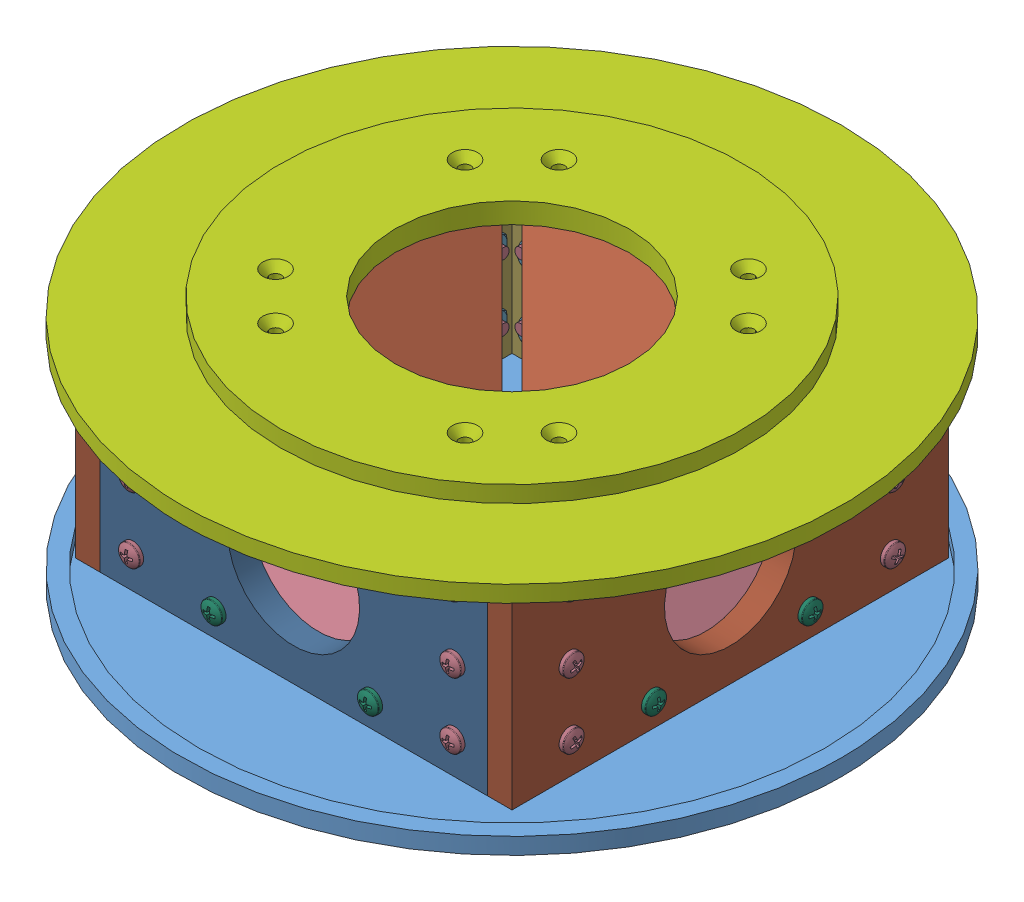
SolidWorks assembly Spinner assembly, configuration Default. Lengths in mm.
Overall size (254 134.94 254).
133 component instances, 16 part files, 69 mates.
Components (placement in the parent):
- bottom spinner plate-1: bottom spinner plate [Default] x (0 0 -1) z (1 0 0) size (254 6.35 254)
- Magnet Assembly-1: Magnet Assembly [Default] at (7.3988 45.9633 51.8347) size (82.55 82.55 29.53)
  - magnet holder-1: magnet holder [Default] at (-7.3988 1.6617 -6.7497) size (82.55 82.55 18.1)
  - Magnet 31-1: Magnet 31 [Default] at (-7.3988 1.6617 -5.1622) x (0.999112 -0.042142 0) z (0 0 1) size (76.2 76.2 25.4)
  - magnet plate-1: magnet plate [Default] at (-7.3988 1.6617 11.3478) size (82.55 82.55 11.43)
  - CR-FHMS 0.164-32x1x1-N-1: CR-FHMS 0.164-32x1x1-N [CR-FHMS 0.164-32x1x1-N] at (-32.7988 36.5867 21.9997) x (0 0 -1) z (-0.169258 0.985572 0) size (25.4 7.42 7.42)
  - CR-FHMS 0.164-32x1x1-N-5: CR-FHMS 0.164-32x1x1-N [CR-FHMS 0.164-32x1x1-N] at (-32.7988 -33.2633 21.9997) x (0 0 -1) z (0.981591 0.190995 0) size (25.4 7.42 7.42)
  - CR-FHMS 0.164-32x1x1-N-6: CR-FHMS 0.164-32x1x1-N [CR-FHMS 0.164-32x1x1-N] at (18.0012 -33.2633 21.9997) x (0 0 -1) z (1 0 0) size (25.4 7.42 7.42)
  - CR-FHMS 0.164-32x1x1-N-7: CR-FHMS 0.164-32x1x1-N [CR-FHMS 0.164-32x1x1-N] at (18.0012 36.5867 21.9997) x (0 0 -1) z (1 0 0) size (25.4 7.42 7.42)
- HX-SHCS 0.19-24x1x1-N-1: HX-SHCS 0.19-24x1x1-N [HX-SHCS 0.19-24x1x1-N] at (-54.61 -4.826 -36.5125) x (0 1 0) z (0 0 1) size (30.23 7.94 7.94)
- top spinner plate-1: top spinner plate [Default] at (0 84.1375 0) size (254 12.7 254)
- Spinner Hub-1: Spinner Hub [Default] x (-0.92388 0 -0.382683) z (-0.382683 0 0.92388) size (76.2 38.1 76.2)
- CR-FHM1 0.164-32x0.875x0.875-N-25: CR-FHM1 0.164-32x0.875x0.875-N [CR-FHM1 0.164-32x0.875x0.875-N] at (0 6.3377 31.75) x (0 -1 0) z (0 0 1) size (22.23 7.24 7.24)
- CR-FHM1 0.164-32x0.875x0.875-N-26: CR-FHM1 0.164-32x0.875x0.875-N [CR-FHM1 0.164-32x0.875x0.875-N] at (22.4506 6.3377 22.4506) x (0 -1 0) z (0.707107 0 0.707107) size (22.23 7.24 7.24)
- CR-FHM1 0.164-32x0.875x0.875-N-27: CR-FHM1 0.164-32x0.875x0.875-N [CR-FHM1 0.164-32x0.875x0.875-N] at (31.75 6.3377 0) x (0 -1 0) z (1 0 0) size (22.23 7.24 7.24)
- CR-FHM1 0.164-32x0.875x0.875-N-28: CR-FHM1 0.164-32x0.875x0.875-N [CR-FHM1 0.164-32x0.875x0.875-N] at (22.4506 6.3377 -22.4506) x (0 -1 0) z (0.707107 0 -0.707107) size (22.23 7.24 7.24)
- CR-FHM1 0.164-32x0.875x0.875-N-29: CR-FHM1 0.164-32x0.875x0.875-N [CR-FHM1 0.164-32x0.875x0.875-N] at (0 6.3377 -31.75) x (0 -1 0) z (0 0 -1) size (22.23 7.24 7.24)
- CR-FHM1 0.164-32x0.875x0.875-N-30: CR-FHM1 0.164-32x0.875x0.875-N [CR-FHM1 0.164-32x0.875x0.875-N] at (-22.4506 6.3377 -22.4506) x (0 -1 0) z (-0.707107 0 -0.707107) size (22.23 7.24 7.24)
- CR-FHM1 0.164-32x0.875x0.875-N-31: CR-FHM1 0.164-32x0.875x0.875-N [CR-FHM1 0.164-32x0.875x0.875-N] at (-31.75 6.3377 0) x (0 -1 0) z (-1 0 0) size (22.23 7.24 7.24)
- CR-FHM1 0.164-32x0.875x0.875-N-32: CR-FHM1 0.164-32x0.875x0.875-N [CR-FHM1 0.164-32x0.875x0.875-N] at (-22.4506 6.3377 22.4506) x (0 -1 0) z (-0.707107 0 0.707107) size (22.23 7.24 7.24)
- Magnet Assembly-5: Magnet Assembly [Default] at (7.3988 49.2867 -51.8347) x (1 0 0) z (0 0 -1) size (82.55 82.55 29.53)
  - magnet holder-1: magnet holder [Default] at (-7.3988 1.6617 -6.7497) size (82.55 82.55 18.1)
  - Magnet 31-1: Magnet 31 [Default] at (-7.3988 1.6617 -5.1622) x (0.999112 -0.042142 0) z (0 0 1) size (76.2 76.2 25.4)
  - magnet plate-1: magnet plate [Default] at (-7.3988 1.6617 11.3478) size (82.55 82.55 11.43)
  - CR-FHMS 0.164-32x1x1-N-1: CR-FHMS 0.164-32x1x1-N [CR-FHMS 0.164-32x1x1-N] at (-32.7988 36.5867 21.9997) x (0 0 -1) z (-0.169258 0.985572 0) size (25.4 7.42 7.42)
  - CR-FHMS 0.164-32x1x1-N-5: CR-FHMS 0.164-32x1x1-N [CR-FHMS 0.164-32x1x1-N] at (-32.7988 -33.2633 21.9997) x (0 0 -1) z (0.981591 0.190995 0) size (25.4 7.42 7.42)
  - CR-FHMS 0.164-32x1x1-N-6: CR-FHMS 0.164-32x1x1-N [CR-FHMS 0.164-32x1x1-N] at (18.0012 -33.2633 21.9997) x (0 0 -1) z (1 0 0) size (25.4 7.42 7.42)
  - CR-FHMS 0.164-32x1x1-N-7: CR-FHMS 0.164-32x1x1-N [CR-FHMS 0.164-32x1x1-N] at (18.0012 36.5867 21.9997) x (0 0 -1) z (1 0 0) size (25.4 7.42 7.42)
- End Shunt-1: End Shunt [Default] at (-74.6125 47.625 -79.375) x (0 0 -1) z (1 0 0) size (9.53 76.2 149.22)
- End Shunt-2: End Shunt [Default] at (74.6125 47.625 79.375) x (0 0 1) z (-1 0 0) size (9.53 76.2 149.22)
- Side Shunt-1: Side Shunt [Default] at (79.375 47.625 -84.1375) size (9.53 76.2 168.28)
- Side Shunt-2: Side Shunt [Default] at (-79.375 47.625 -84.1375) size (9.53 76.2 168.28)
- Shunt Gusset-1: Shunt Gusset [Default] at (74.6125 85.725 74.6125) x (-1 0 0) z (0 -1 0) size (25.4 25.4 79.38)
- CR-PHMS 0.164-32x0.75x0.75-N-1: CR-PHMS 0.164-32x0.75x0.75-N [CR-PHMS 0.164-32x0.75x0.75-N] at (87.0585 73.025 61.9125) x (-1 0 0) z (0 0.924225 0.381849) size (21.93 8.18 8.18)
- CR-PHMS 0.164-32x0.75x0.75-N-2: CR-PHMS 0.164-32x0.75x0.75-N [CR-PHMS 0.164-32x0.75x0.75-N] at (87.0585 47.625 61.9125) x (-1 0 0) z (0 0.924225 0.381849) size (21.93 8.18 8.18)
- CR-PHMS 0.164-32x0.75x0.75-N-3: CR-PHMS 0.164-32x0.75x0.75-N [CR-PHMS 0.164-32x0.75x0.75-N] at (87.0585 22.225 61.9125) x (-1 0 0) z (0 0.924225 0.381849) size (21.93 8.18 8.18)
- CR-PHMS 0.164-32x0.75x0.75-N-4: CR-PHMS 0.164-32x0.75x0.75-N [CR-PHMS 0.164-32x0.75x0.75-N] at (61.9125 22.225 87.0585) x (0 0 -1) z (1 0 0) size (21.93 8.18 8.18)
- CR-PHMS 0.164-32x0.75x0.75-N-5: CR-PHMS 0.164-32x0.75x0.75-N [CR-PHMS 0.164-32x0.75x0.75-N] at (61.9125 47.625 87.0585) x (0 0 -1) z (1 0 0) size (21.93 8.18 8.18)
- CR-PHMS 0.164-32x0.75x0.75-N-6: CR-PHMS 0.164-32x0.75x0.75-N [CR-PHMS 0.164-32x0.75x0.75-N] at (61.9125 73.025 87.0585) x (0 0 -1) z (1 0 0) size (21.93 8.18 8.18)
- MSHXNUT 0.164-32-S-N-66: MSHXNUT 0.164-32-S-N [MSHXNUT 0.164-32-S-N] at (68.1355 73.025 61.9125) x (0 0 1) z (-1 0 0) size (8.74 10.09 3.3)
- MSHXNUT 0.164-32-S-N-67: MSHXNUT 0.164-32-S-N [MSHXNUT 0.164-32-S-N] at (68.1355 47.625 61.9125) x (0 0 1) z (-1 0 0) size (8.74 10.09 3.3)
- MSHXNUT 0.164-32-S-N-68: MSHXNUT 0.164-32-S-N [MSHXNUT 0.164-32-S-N] at (61.9125 69.85 68.1355) x (0.923728 0.383049 0) z (0 0 -1) size (8.74 10.09 3.3)
- MSHXNUT 0.164-32-S-N-69: MSHXNUT 0.164-32-S-N [MSHXNUT 0.164-32-S-N] at (61.9125 44.45 68.1355) x (0.923728 0.383049 0) z (0 0 -1) size (8.74 10.09 3.3)
- MSHXNUT 0.164-32-S-N-70: MSHXNUT 0.164-32-S-N [MSHXNUT 0.164-32-S-N] at (61.9125 19.05 68.1355) x (0.923728 0.383049 0) z (0 0 -1) size (8.74 10.09 3.3)
- MSHXNUT 0.164-32-S-N-71: MSHXNUT 0.164-32-S-N [MSHXNUT 0.164-32-S-N] at (68.1355 22.225 61.9125) x (0 0 1) z (-1 0 0) size (8.74 10.09 3.3)
- CR-PHMS 0.164-32x1.25x1-N-7: CR-PHMS 0.164-32x1.25x1-N [CR-PHMS 0.164-32x1.25x1-N] at (30.1625 76.2 87.0585) x (0 0 -1) z (1 0 0) size (34.63 8.18 8.18)
- CR-PHMS 0.164-32x1.25x1-N-8: CR-PHMS 0.164-32x1.25x1-N [CR-PHMS 0.164-32x1.25x1-N] at (30.1625 19.05 87.0585) x (0 0 -1) z (1 0 0) size (34.63 8.18 8.18)
- CR-PHMS 0.164-32x1.25x1-N-9: CR-PHMS 0.164-32x1.25x1-N [CR-PHMS 0.164-32x1.25x1-N] at (-30.1625 19.05 87.0585) x (0 0 -1) z (1 0 0) size (34.63 8.18 8.18)
- CR-PHMS 0.164-32x1.25x1-N-10: CR-PHMS 0.164-32x1.25x1-N [CR-PHMS 0.164-32x1.25x1-N] at (-30.1625 76.2 87.0585) x (0 0 -1) z (1 0 0) size (34.63 8.18 8.18)
- MSHXNUT 0.164-32-S-N-72: MSHXNUT 0.164-32-S-N [MSHXNUT 0.164-32-S-N] at (0 -12.827 31.75) x (1 0 0) z (0 -1 0) size (8.74 10.09 3.3)
- MSHXNUT 0.164-32-S-N-80: MSHXNUT 0.164-32-S-N [MSHXNUT 0.164-32-S-N] at (22.4506 -12.827 22.4506) x (0.707107 0 -0.707107) z (0 -1 0) size (8.74 10.09 3.3)
- MSHXNUT 0.164-32-S-N-81: MSHXNUT 0.164-32-S-N [MSHXNUT 0.164-32-S-N] at (31.75 -12.827 0) x (0 0 -1) z (0 -1 0) size (8.74 10.09 3.3)
- MSHXNUT 0.164-32-S-N-82: MSHXNUT 0.164-32-S-N [MSHXNUT 0.164-32-S-N] at (22.4506 -12.827 -22.4506) x (-0.707107 0 -0.707107) z (0 -1 0) size (8.74 10.09 3.3)
- MSHXNUT 0.164-32-S-N-83: MSHXNUT 0.164-32-S-N [MSHXNUT 0.164-32-S-N] at (0 -12.827 -31.75) x (-1 0 0) z (0 -1 0) size (8.74 10.09 3.3)
- MSHXNUT 0.164-32-S-N-84: MSHXNUT 0.164-32-S-N [MSHXNUT 0.164-32-S-N] at (-22.4506 -12.827 -22.4506) x (-0.707107 0 0.707107) z (0 -1 0) size (8.74 10.09 3.3)
- MSHXNUT 0.164-32-S-N-85: MSHXNUT 0.164-32-S-N [MSHXNUT 0.164-32-S-N] at (-31.75 -12.827 0) x (0 0 1) z (0 -1 0) size (8.74 10.09 3.3)
- MSHXNUT 0.164-32-S-N-86: MSHXNUT 0.164-32-S-N [MSHXNUT 0.164-32-S-N] at (-22.4506 -12.827 22.4506) x (0.707107 0 0.707107) z (0 -1 0) size (8.74 10.09 3.3)
- CR-PHMS 0.164-32x1.25x1-N-29: CR-PHMS 0.164-32x1.25x1-N [CR-PHMS 0.164-32x1.25x1-N] at (-30.1625 76.2 -87.0585) x (0 0 1) z (-1 0 0) size (34.63 8.18 8.18)
- CR-PHMS 0.164-32x1.25x1-N-30: CR-PHMS 0.164-32x1.25x1-N [CR-PHMS 0.164-32x1.25x1-N] at (-30.1625 19.05 -87.0585) x (0 0 1) z (-1 0 0) size (34.63 8.18 8.18)
- CR-PHMS 0.164-32x1.25x1-N-31: CR-PHMS 0.164-32x1.25x1-N [CR-PHMS 0.164-32x1.25x1-N] at (30.1625 76.2 -87.0585) x (0 0 1) z (-1 0 0) size (34.63 8.18 8.18)
- CR-PHMS 0.164-32x1.25x1-N-32: CR-PHMS 0.164-32x1.25x1-N [CR-PHMS 0.164-32x1.25x1-N] at (30.1625 19.05 -87.0585) x (0 0 1) z (-1 0 0) size (34.63 8.18 8.18)
- CR-PHMS 0.164-32x0.75x0.75-N-33: CR-PHMS 0.164-32x0.75x0.75-N [CR-PHMS 0.164-32x0.75x0.75-N] at (-87.0585 73.025 61.9125) x (1 0 0) z (0 -0.924225 -0.381849) size (21.93 8.18 8.18)
- CR-PHMS 0.164-32x0.75x0.75-N-34: CR-PHMS 0.164-32x0.75x0.75-N [CR-PHMS 0.164-32x0.75x0.75-N] at (-87.0585 47.625 61.9125) x (1 0 0) z (0 -0.924225 -0.381849) size (21.93 8.18 8.18)
- CR-PHMS 0.164-32x0.75x0.75-N-35: CR-PHMS 0.164-32x0.75x0.75-N [CR-PHMS 0.164-32x0.75x0.75-N] at (-87.0585 22.225 61.9125) x (1 0 0) z (0 -0.924225 -0.381849) size (21.93 8.18 8.18)
- CR-PHMS 0.164-32x0.75x0.75-N-36: CR-PHMS 0.164-32x0.75x0.75-N [CR-PHMS 0.164-32x0.75x0.75-N] at (-61.9125 73.025 87.0585) x (0 0 -1) z (1 0 0) size (21.93 8.18 8.18)
- CR-PHMS 0.164-32x0.75x0.75-N-37: CR-PHMS 0.164-32x0.75x0.75-N [CR-PHMS 0.164-32x0.75x0.75-N] at (-61.9125 47.625 87.0585) x (0 0 -1) z (1 0 0) size (21.93 8.18 8.18)
- CR-PHMS 0.164-32x0.75x0.75-N-38: CR-PHMS 0.164-32x0.75x0.75-N [CR-PHMS 0.164-32x0.75x0.75-N] at (-61.9125 22.225 87.0585) x (0 0 -1) z (1 0 0) size (21.93 8.18 8.18)
- Shunt Gusset-2: Shunt Gusset [Default] at (-74.6125 6.35 74.6125) x (1 0 0) z (0 1 0) size (25.4 25.4 79.38)
- MSHXNUT 0.164-32-S-N-90: MSHXNUT 0.164-32-S-N [MSHXNUT 0.164-32-S-N] at (-61.9125 69.85 68.1355) x (0.923728 -0.383049 0) z (0 0 -1) size (8.74 10.09 3.3)
- MSHXNUT 0.164-32-S-N-91: MSHXNUT 0.164-32-S-N [MSHXNUT 0.164-32-S-N] at (-61.9125 44.45 68.1355) x (0.923728 -0.383049 0) z (0 0 -1) size (8.74 10.09 3.3)
- MSHXNUT 0.164-32-S-N-92: MSHXNUT 0.164-32-S-N [MSHXNUT 0.164-32-S-N] at (-61.9125 19.05 68.1355) x (0.923728 -0.383049 0) z (0 0 -1) size (8.74 10.09 3.3)
- MSHXNUT 0.164-32-S-N-93: MSHXNUT 0.164-32-S-N [MSHXNUT 0.164-32-S-N] at (-68.1355 22.225 61.9125) x (0 0 -1) z (1 0 0) size (8.74 10.09 3.3)
- MSHXNUT 0.164-32-S-N-94: MSHXNUT 0.164-32-S-N [MSHXNUT 0.164-32-S-N] at (-68.1355 47.625 61.9125) x (0 0 -1) z (1 0 0) size (8.74 10.09 3.3)
- MSHXNUT 0.164-32-S-N-87: MSHXNUT 0.164-32-S-N [MSHXNUT 0.164-32-S-N] at (-68.1355 73.025 61.9125) x (0 0 -1) z (1 0 0) size (8.74 10.09 3.3)
- CR-PHMS 0.164-32x0.75x0.75-N-39: CR-PHMS 0.164-32x0.75x0.75-N [CR-PHMS 0.164-32x0.75x0.75-N] at (87.0585 73.025 -61.9125) x (-1 0 0) z (0 -0.924225 0.381849) size (21.93 8.18 8.18)
- CR-PHMS 0.164-32x0.75x0.75-N-40: CR-PHMS 0.164-32x0.75x0.75-N [CR-PHMS 0.164-32x0.75x0.75-N] at (87.0585 47.625 -61.9125) x (-1 0 0) z (0 -0.924225 0.381849) size (21.93 8.18 8.18)
- CR-PHMS 0.164-32x0.75x0.75-N-41: CR-PHMS 0.164-32x0.75x0.75-N [CR-PHMS 0.164-32x0.75x0.75-N] at (87.0585 22.225 -61.9125) x (-1 0 0) z (0 -0.924225 0.381849) size (21.93 8.18 8.18)
- CR-PHMS 0.164-32x0.75x0.75-N-42: CR-PHMS 0.164-32x0.75x0.75-N [CR-PHMS 0.164-32x0.75x0.75-N] at (61.9125 73.025 -87.0585) x (0 0 1) z (-1 0 0) size (21.93 8.18 8.18)
- CR-PHMS 0.164-32x0.75x0.75-N-43: CR-PHMS 0.164-32x0.75x0.75-N [CR-PHMS 0.164-32x0.75x0.75-N] at (61.9125 47.625 -87.0585) x (0 0 1) z (-1 0 0) size (21.93 8.18 8.18)
- CR-PHMS 0.164-32x0.75x0.75-N-44: CR-PHMS 0.164-32x0.75x0.75-N [CR-PHMS 0.164-32x0.75x0.75-N] at (61.9125 22.225 -87.0585) x (0 0 1) z (-1 0 0) size (21.93 8.18 8.18)
- Shunt Gusset-3: Shunt Gusset [Default] at (74.6125 6.35 -74.6125) x (-1 0 0) z (0 1 0) size (25.4 25.4 79.38)
- MSHXNUT 0.164-32-S-N-95: MSHXNUT 0.164-32-S-N [MSHXNUT 0.164-32-S-N] at (61.9125 69.85 -68.1355) x (-0.923728 -0.383049 0) z (0 0 1) size (8.74 10.09 3.3)
- MSHXNUT 0.164-32-S-N-96: MSHXNUT 0.164-32-S-N [MSHXNUT 0.164-32-S-N] at (61.9125 44.45 -68.1355) x (-0.923728 -0.383049 0) z (0 0 1) size (8.74 10.09 3.3)
- MSHXNUT 0.164-32-S-N-97: MSHXNUT 0.164-32-S-N [MSHXNUT 0.164-32-S-N] at (61.9125 19.05 -68.1355) x (-0.923728 -0.383049 0) z (0 0 1) size (8.74 10.09 3.3)
- MSHXNUT 0.164-32-S-N-98: MSHXNUT 0.164-32-S-N [MSHXNUT 0.164-32-S-N] at (68.1355 22.225 -61.9125) x (0 0 1) z (-1 0 0) size (8.74 10.09 3.3)
- MSHXNUT 0.164-32-S-N-99: MSHXNUT 0.164-32-S-N [MSHXNUT 0.164-32-S-N] at (68.1355 47.625 -61.9125) x (0 0 1) z (-1 0 0) size (8.74 10.09 3.3)
- MSHXNUT 0.164-32-S-N-88: MSHXNUT 0.164-32-S-N [MSHXNUT 0.164-32-S-N] at (68.1355 73.025 -61.9125) x (0 0 1) z (-1 0 0) size (8.74 10.09 3.3)
- CR-PHMS 0.164-32x0.75x0.75-N-45: CR-PHMS 0.164-32x0.75x0.75-N [CR-PHMS 0.164-32x0.75x0.75-N] at (-87.0585 73.025 -61.9125) x (1 0 0) z (0 0.924225 -0.381849) size (21.93 8.18 8.18)
- CR-PHMS 0.164-32x0.75x0.75-N-46: CR-PHMS 0.164-32x0.75x0.75-N [CR-PHMS 0.164-32x0.75x0.75-N] at (-87.0585 47.625 -61.9125) x (1 0 0) z (0 0.924225 -0.381849) size (21.93 8.18 8.18)
- CR-PHMS 0.164-32x0.75x0.75-N-47: CR-PHMS 0.164-32x0.75x0.75-N [CR-PHMS 0.164-32x0.75x0.75-N] at (-87.0585 22.225 -61.9125) x (1 0 0) z (0 0.924225 -0.381849) size (21.93 8.18 8.18)
- CR-PHMS 0.164-32x0.75x0.75-N-48: CR-PHMS 0.164-32x0.75x0.75-N [CR-PHMS 0.164-32x0.75x0.75-N] at (-61.9125 73.025 -87.0585) x (0 0 1) z (-1 0 0) size (21.93 8.18 8.18)
- CR-PHMS 0.164-32x0.75x0.75-N-49: CR-PHMS 0.164-32x0.75x0.75-N [CR-PHMS 0.164-32x0.75x0.75-N] at (-61.9125 47.625 -87.0585) x (0 0 1) z (-1 0 0) size (21.93 8.18 8.18)
- CR-PHMS 0.164-32x0.75x0.75-N-50: CR-PHMS 0.164-32x0.75x0.75-N [CR-PHMS 0.164-32x0.75x0.75-N] at (-61.9125 22.225 -87.0585) x (0 0 1) z (-1 0 0) size (21.93 8.18 8.18)
- Shunt Gusset-4: Shunt Gusset [Default] at (-74.6125 85.725 -74.6125) x (1 0 0) z (0 -1 0) size (25.4 25.4 79.38)
- MSHXNUT 0.164-32-S-N-100: MSHXNUT 0.164-32-S-N [MSHXNUT 0.164-32-S-N] at (-61.9125 69.85 -68.1355) x (-0.923728 0.383049 0) z (0 0 1) size (8.74 10.09 3.3)
- MSHXNUT 0.164-32-S-N-101: MSHXNUT 0.164-32-S-N [MSHXNUT 0.164-32-S-N] at (-61.9125 44.45 -68.1355) x (-0.923728 0.383049 0) z (0 0 1) size (8.74 10.09 3.3)
- MSHXNUT 0.164-32-S-N-102: MSHXNUT 0.164-32-S-N [MSHXNUT 0.164-32-S-N] at (-61.9125 19.05 -68.1355) x (-0.923728 0.383049 0) z (0 0 1) size (8.74 10.09 3.3)
- MSHXNUT 0.164-32-S-N-103: MSHXNUT 0.164-32-S-N [MSHXNUT 0.164-32-S-N] at (-68.1355 22.225 -61.9125) x (0 0 -1) z (1 0 0) size (8.74 10.09 3.3)
- MSHXNUT 0.164-32-S-N-104: MSHXNUT 0.164-32-S-N [MSHXNUT 0.164-32-S-N] at (-68.1355 47.625 -61.9125) x (0 0 -1) z (1 0 0) size (8.74 10.09 3.3)
- MSHXNUT 0.164-32-S-N-89: MSHXNUT 0.164-32-S-N [MSHXNUT 0.164-32-S-N] at (-68.1355 73.025 -61.9125) x (0 0 -1) z (1 0 0) size (8.74 10.09 3.3)
- CR-PHMS 0.164-32x1.25x1-N-51: CR-PHMS 0.164-32x1.25x1-N [CR-PHMS 0.164-32x1.25x1-N] at (-30.1625 76.2 -87.0585) x (0 0 1) z (-1 0 0) size (34.63 8.18 8.18)
- CR-PHMS 0.164-32x1.25x1-N-52: CR-PHMS 0.164-32x1.25x1-N [CR-PHMS 0.164-32x1.25x1-N] at (-30.1625 19.05 -87.0585) x (0 0 1) z (-1 0 0) size (34.63 8.18 8.18)
- CR-PHMS 0.164-32x1.25x1-N-53: CR-PHMS 0.164-32x1.25x1-N [CR-PHMS 0.164-32x1.25x1-N] at (30.1625 76.2 -87.0585) x (0 0 1) z (-1 0 0) size (34.63 8.18 8.18)
- CR-PHMS 0.164-32x1.25x1-N-54: CR-PHMS 0.164-32x1.25x1-N [CR-PHMS 0.164-32x1.25x1-N] at (30.1625 19.05 -87.0585) x (0 0 1) z (-1 0 0) size (34.63 8.18 8.18)
- CR-PHMS 0.164-32x1.25x1-N-55: CR-PHMS 0.164-32x1.25x1-N [CR-PHMS 0.164-32x1.25x1-N] at (-30.1625 76.2 87.0585) x (0 0 -1) z (1 0 0) size (34.63 8.18 8.18)
- CR-PHMS 0.164-32x1.25x1-N-56: CR-PHMS 0.164-32x1.25x1-N [CR-PHMS 0.164-32x1.25x1-N] at (-30.1625 19.05 87.0585) x (0 0 -1) z (1 0 0) size (34.63 8.18 8.18)
- CR-PHMS 0.164-32x1.25x1-N-57: CR-PHMS 0.164-32x1.25x1-N [CR-PHMS 0.164-32x1.25x1-N] at (30.1625 76.2 87.0585) x (0 0 -1) z (1 0 0) size (34.63 8.18 8.18)
- CR-PHMS 0.164-32x1.25x1-N-58: CR-PHMS 0.164-32x1.25x1-N [CR-PHMS 0.164-32x1.25x1-N] at (30.1625 19.05 87.0585) x (0 0 -1) z (1 0 0) size (34.63 8.18 8.18)
- Magnet Assembly-6: Magnet Assembly [Default] at (-51.8347 45.9633 7.3988) x (0 0 1) z (-1 0 0) size (82.55 82.55 29.53)
  - magnet holder-1: magnet holder [Default] at (-7.3988 1.6617 -6.7497) size (82.55 82.55 18.1)
  - Magnet 31-1: Magnet 31 [Default] at (-7.3988 1.6617 -5.1622) x (0.999112 -0.042142 0) z (0 0 1) size (76.2 76.2 25.4)
  - magnet plate-1: magnet plate [Default] at (-7.3988 1.6617 11.3478) size (82.55 82.55 11.43)
  - CR-FHMS 0.164-32x1x1-N-1: CR-FHMS 0.164-32x1x1-N [CR-FHMS 0.164-32x1x1-N] at (-32.7988 36.5867 21.9997) x (0 0 -1) z (-0.169258 0.985572 0) size (25.4 7.42 7.42)
  - CR-FHMS 0.164-32x1x1-N-5: CR-FHMS 0.164-32x1x1-N [CR-FHMS 0.164-32x1x1-N] at (-32.7988 -33.2633 21.9997) x (0 0 -1) z (0.981591 0.190995 0) size (25.4 7.42 7.42)
  - CR-FHMS 0.164-32x1x1-N-6: CR-FHMS 0.164-32x1x1-N [CR-FHMS 0.164-32x1x1-N] at (18.0012 -33.2633 21.9997) x (0 0 -1) z (1 0 0) size (25.4 7.42 7.42)
  - CR-FHMS 0.164-32x1x1-N-7: CR-FHMS 0.164-32x1x1-N [CR-FHMS 0.164-32x1x1-N] at (18.0012 36.5867 21.9997) x (0 0 -1) z (1 0 0) size (25.4 7.42 7.42)
- Magnet Assembly-7: Magnet Assembly [Default] at (51.8347 49.2867 7.3988) x (0 0 1) z (1 0 0) size (82.55 82.55 29.53)
  - magnet holder-1: magnet holder [Default] at (-7.3988 1.6617 -6.7497) size (82.55 82.55 18.1)
  - Magnet 31-1: Magnet 31 [Default] at (-7.3988 1.6617 -5.1622) x (0.999112 -0.042142 0) z (0 0 1) size (76.2 76.2 25.4)
  - magnet plate-1: magnet plate [Default] at (-7.3988 1.6617 11.3478) size (82.55 82.55 11.43)
  - CR-FHMS 0.164-32x1x1-N-1: CR-FHMS 0.164-32x1x1-N [CR-FHMS 0.164-32x1x1-N] at (-32.7988 36.5867 21.9997) x (0 0 -1) z (-0.169258 0.985572 0) size (25.4 7.42 7.42)
  - CR-FHMS 0.164-32x1x1-N-5: CR-FHMS 0.164-32x1x1-N [CR-FHMS 0.164-32x1x1-N] at (-32.7988 -33.2633 21.9997) x (0 0 -1) z (0.981591 0.190995 0) size (25.4 7.42 7.42)
  - CR-FHMS 0.164-32x1x1-N-6: CR-FHMS 0.164-32x1x1-N [CR-FHMS 0.164-32x1x1-N] at (18.0012 -33.2633 21.9997) x (0 0 -1) z (1 0 0) size (25.4 7.42 7.42)
  - CR-FHMS 0.164-32x1x1-N-7: CR-FHMS 0.164-32x1x1-N [CR-FHMS 0.164-32x1x1-N] at (18.0012 36.5867 21.9997) x (0 0 -1) z (1 0 0) size (25.4 7.42 7.42)
- CR-PHMS 0.164-32x1.25x1-N-59: CR-PHMS 0.164-32x1.25x1-N [CR-PHMS 0.164-32x1.25x1-N] at (-87.0585 19.05 30.1625) size (34.63 8.18 8.18)
- CR-PHMS 0.164-32x1.25x1-N-60: CR-PHMS 0.164-32x1.25x1-N [CR-PHMS 0.164-32x1.25x1-N] at (-87.0585 76.2 30.1625) size (34.63 8.18 8.18)
- CR-PHMS 0.164-32x1.25x1-N-61: CR-PHMS 0.164-32x1.25x1-N [CR-PHMS 0.164-32x1.25x1-N] at (-87.0585 76.2 -30.1625) size (34.63 8.18 8.18)
- CR-PHMS 0.164-32x1.25x1-N-62: CR-PHMS 0.164-32x1.25x1-N [CR-PHMS 0.164-32x1.25x1-N] at (-87.0585 19.05 -30.1625) size (34.63 8.18 8.18)
- CR-PHMS 0.164-32x1.25x1-N-63: CR-PHMS 0.164-32x1.25x1-N [CR-PHMS 0.164-32x1.25x1-N] at (87.0585 19.05 30.1625) x (-1 0 0) z (0 0 -1) size (34.63 8.18 8.18)
- CR-PHMS 0.164-32x1.25x1-N-64: CR-PHMS 0.164-32x1.25x1-N [CR-PHMS 0.164-32x1.25x1-N] at (87.0585 19.05 -30.1625) x (-1 0 0) z (0 0 -1) size (34.63 8.18 8.18)
- CR-PHMS 0.164-32x1.25x1-N-65: CR-PHMS 0.164-32x1.25x1-N [CR-PHMS 0.164-32x1.25x1-N] at (87.0585 76.2 -30.1625) x (-1 0 0) z (0 0 -1) size (34.63 8.18 8.18)
- CR-PHMS 0.164-32x1.25x1-N-66: CR-PHMS 0.164-32x1.25x1-N [CR-PHMS 0.164-32x1.25x1-N] at (87.0585 76.2 30.1625) x (-1 0 0) z (0 0 -1) size (34.63 8.18 8.18)
- Aero Cowling-1: Aero Cowling [Default] at origin size (257.18 88.9 257.18) (hidden)
Mates (geometry in assembly coordinates):
- Concentric1: concentric aligned: circle of Magnet Assembly-1/magnet holder-1; cylinder of bottom spinner plate-1 through (36.5125 6.35 54.61) axis (0 1 0) radius 2.5527
- Concentric2: concentric aligned: circle of Magnet Assembly-1/magnet holder-1; cylinder of bottom spinner plate-1 through (-36.5125 6.35 54.61) axis (0 1 0) radius 2.5527
- Coincident1: coincident anti-aligned: plane of bottom spinner plate-1 through (0 6.35 0) normal (0 1 0); plane of Magnet Assembly-1/magnet holder-1 through (41.275 6.35 63.1825) normal (0 -1 0)
- Concentric3: concentric anti-aligned: cylinder of HX-SHCS 0.19-24x1x1-N-1 through (-54.61 -36.576 -36.5125) axis (0 -1 0) radius 2.413; cylinder of bottom spinner plate-1 through (-54.61 6.35 -36.5125) axis (0 1 0) radius 2.5527
- Coincident3: coincident aligned: plane of bottom spinner plate-1 through (0 0 0) normal (0 -1 0); circle of HX-SHCS 0.19-24x1x1-N-1
- Coincident5: coincident anti-aligned: plane of Magnet Assembly-1/magnet holder-1 through (41.275 88.9 63.1825) normal (0 1 0); plane of top spinner plate-1 through (0 88.9 0) normal (0 -1 0)
- Coincident9: coincident anti-aligned: plane of bottom spinner plate-1 through (0 0 0) normal (0 -1 0); plane of Spinner Hub-1 through (0 0 0) normal (0 1 0)
- Concentric15: concentric anti-aligned: circle of Spinner Hub-1; cylinder of CR-FHM1 0.164-32x0.875x0.875-N-25 through (0 12.6877 31.75) axis (0 1 0) radius 2.0828
- Coincident10: coincident aligned: cone of bottom spinner plate-1 through (0 6.35 31.75) axis (0 -1 0); cone of CR-FHM1 0.164-32x0.875x0.875-N-25 through (0 5.8491 31.75) axis (0 -1 0)
- Concentric18: concentric aligned: circle of bottom spinner plate-1; circle of Spinner Hub-1
- Coincident11: coincident: axis of Spinner Hub-1 through (9.525 0 -9.525) axis (0 0 1); plane of assembly
- Coincident12: coincident: axis of Spinner Hub-1 through (9.525 0 -9.525) axis (0 0 1); plane of assembly
- Coincident14: coincident anti-aligned: plane of bottom spinner plate-1 through (0 0 0) normal (0 -1 0); plane of assembly through (0 0 0) normal (0 1 0)
- Coincident15: coincident anti-aligned: plane of Magnet Assembly-1/magnet plate-1 through (-41.275 88.9 74.6125) normal (0 0 1); plane of End Shunt-2 through (-74.6125 85.725 74.6125) normal (0 0 -1)
- Coincident16: coincident anti-aligned: plane of Magnet Assembly-5/magnet plate-1 through (-41.275 6.35 -74.6125) normal (0 0 -1); plane of End Shunt-1 through (74.6125 85.725 -74.6125) normal (0 0 1)
- Coincident17: coincident aligned: plane of End Shunt-1 through (74.6125 85.725 -74.6125) normal (0 1 0); plane of End Shunt-2 through (-74.6125 85.725 74.6125) normal (0 1 0)
- Coincident18: coincident anti-aligned: plane of End Shunt-1 through (-74.6125 47.625 -79.375) normal (-1 0 0); plane of Side Shunt-2 through (-74.6125 85.725 84.1375) normal (1 0 0)
- Coincident19: coincident anti-aligned: plane of End Shunt-2 through (-74.6125 47.625 79.375) normal (-1 0 0); plane of Side Shunt-2 through (-74.6125 85.725 84.1375) normal (1 0 0)
- Coincident20: coincident aligned: plane of End Shunt-2 through (-74.6125 85.725 74.6125) normal (0 1 0); plane of Side Shunt-2 through (-84.1375 85.725 84.1375) normal (0 1 0)
- Coincident21: coincident aligned: plane of End Shunt-1 through (74.6125 85.725 -84.1375) normal (0 0 -1); plane of Side Shunt-2 through (-79.375 47.625 -84.1375) normal (0 0 -1)
- Coincident24: coincident anti-aligned: plane of End Shunt-1 through (74.6125 47.625 -79.375) normal (1 0 0); plane of Side Shunt-1 through (74.6125 85.725 84.1375) normal (-1 0 0)
- Coincident25: coincident aligned: plane of End Shunt-1 through (74.6125 85.725 -74.6125) normal (0 1 0); plane of Side Shunt-1 through (74.6125 85.725 84.1375) normal (0 1 0)
- Coincident26: coincident aligned: plane of End Shunt-1 through (74.6125 85.725 -84.1375) normal (0 0 -1); plane of Side Shunt-1 through (79.375 47.625 -84.1375) normal (0 0 -1)
- Concentric19: concentric aligned: cylinder of Magnet Assembly-5/magnet plate-1 through (-30.1625 19.05 -74.6125) axis (0 0 -1) radius 2.2479; cylinder of End Shunt-1 through (-30.1625 19.05 -84.1375) axis (0 0 -1) radius 2.2479
- Concentric20: concentric aligned: cylinder of Magnet Assembly-5/magnet plate-1 through (30.1625 19.05 -74.6125) axis (0 0 -1) radius 2.2479; cylinder of End Shunt-1 through (30.1625 19.05 -84.1375) axis (0 0 -1) radius 2.2479
- Coincident27: coincident anti-aligned: plane of Side Shunt-1 through (74.6125 85.725 84.1375) normal (-1 0 0); plane of Shunt Gusset-1 through (74.6125 6.35 74.6125) normal (1 0 0)
- Coincident28: coincident anti-aligned: plane of End Shunt-2 through (-74.6125 85.725 74.6125) normal (0 0 -1); plane of Shunt Gusset-1 through (74.6125 6.35 74.6125) normal (0 0 1)
- Coincident29: coincident aligned: plane of Side Shunt-1 through (74.6125 85.725 84.1375) normal (0 1 0); plane of Shunt Gusset-1 through (74.6125 85.725 74.6125) normal (0 1 0)
- Concentric21: concentric aligned: cylinder of Side Shunt-1 through (84.1375 73.025 61.9125) axis (1 0 0) radius 2.2479; cylinder of CR-PHMS 0.164-32x0.75x0.75-N-1 through (112.4585 73.025 61.9125) axis (1 0 0) radius 4.0894
- Coincident30: coincident anti-aligned: plane of Side Shunt-1 through (84.1375 85.725 84.1375) normal (1 0 0); plane of CR-PHMS 0.164-32x0.75x0.75-N-1 through (84.1375 72.2297 63.8375) normal (-1 0 0)
- Concentric22: concentric aligned: cylinder of Side Shunt-1 through (84.1375 47.625 61.9125) axis (1 0 0) radius 2.2479; cylinder of CR-PHMS 0.164-32x0.75x0.75-N-2 through (112.4585 47.625 61.9125) axis (1 0 0) radius 4.0894
- Coincident31: coincident anti-aligned: plane of Side Shunt-1 through (84.1375 85.725 84.1375) normal (1 0 0); plane of CR-PHMS 0.164-32x0.75x0.75-N-2 through (84.1375 46.8297 63.8375) normal (-1 0 0)
- Concentric23: concentric aligned: cylinder of Side Shunt-1 through (84.1375 22.225 61.9125) axis (1 0 0) radius 2.2479; cylinder of CR-PHMS 0.164-32x0.75x0.75-N-3 through (112.4585 22.225 61.9125) axis (1 0 0) radius 4.0894
- Coincident32: coincident anti-aligned: plane of Side Shunt-1 through (84.1375 85.725 84.1375) normal (1 0 0); plane of CR-PHMS 0.164-32x0.75x0.75-N-3 through (84.1375 21.4297 63.8375) normal (-1 0 0)
- Concentric24: concentric aligned: cylinder of End Shunt-2 through (61.9125 22.225 84.1375) axis (0 0 1) radius 2.2479; cylinder of CR-PHMS 0.164-32x0.75x0.75-N-4 through (61.9125 22.225 112.4585) axis (0 0 1) radius 4.0894
- Coincident33: coincident anti-aligned: plane of End Shunt-2 through (-74.6125 85.725 84.1375) normal (0 0 1); plane of CR-PHMS 0.164-32x0.75x0.75-N-4 through (61.9125 24.3078 84.1375) normal (0 0 -1)
- Concentric25: concentric aligned: cylinder of End Shunt-2 through (61.9125 47.625 84.1375) axis (0 0 1) radius 2.2479; cylinder of CR-PHMS 0.164-32x0.75x0.75-N-5 through (61.9125 47.625 112.4585) axis (0 0 1) radius 4.0894
- Coincident34: coincident anti-aligned: plane of End Shunt-2 through (-74.6125 85.725 84.1375) normal (0 0 1); plane of CR-PHMS 0.164-32x0.75x0.75-N-5 through (61.9125 49.7078 84.1375) normal (0 0 -1)
- Concentric26: concentric aligned: cylinder of End Shunt-2 through (61.9125 73.025 84.1375) axis (0 0 1) radius 2.2479; cylinder of CR-PHMS 0.164-32x0.75x0.75-N-6 through (61.9125 73.025 112.4585) axis (0 0 1) radius 4.0894
- Coincident35: coincident anti-aligned: plane of End Shunt-2 through (-74.6125 85.725 84.1375) normal (0 0 1); plane of CR-PHMS 0.164-32x0.75x0.75-N-6 through (61.9125 75.1078 84.1375) normal (0 0 -1)
- Concentric27: concentric anti-aligned: cylinder of Shunt Gusset-1 through (74.6125 73.025 61.9125) axis (1 0 0) radius 2.2479; cylinder of MSHXNUT 0.164-32-S-N-66 through (93.173 73.025 61.9125) axis (-1 0 0) radius 2.0828
- Coincident36: coincident anti-aligned: plane of Shunt Gusset-1 through (71.4375 6.35 49.2125) normal (-1 0 0); plane of MSHXNUT 0.164-32-S-N-66 through (71.4375 78.0697 61.9125) normal (1 0 0)
- Concentric28: concentric anti-aligned: cylinder of Shunt Gusset-1 through (74.6125 47.625 61.9125) axis (1 0 0) radius 2.2479; cylinder of MSHXNUT 0.164-32-S-N-67 through (93.173 47.625 61.9125) axis (-1 0 0) radius 2.0828
- Coincident37: coincident anti-aligned: plane of Shunt Gusset-1 through (71.4375 6.35 49.2125) normal (-1 0 0); plane of MSHXNUT 0.164-32-S-N-67 through (71.4375 52.6697 61.9125) normal (1 0 0)
- Concentric29: concentric anti-aligned: cylinder of Shunt Gusset-1 through (61.9125 69.85 74.6125) axis (0 0 1) radius 2.2479; cylinder of MSHXNUT 0.164-32-S-N-68 through (61.9125 69.85 93.173) axis (0 0 -1) radius 2.0828
- Coincident38: coincident anti-aligned: plane of Shunt Gusset-1 through (49.2125 6.35 71.4375) normal (0 0 -1); plane of MSHXNUT 0.164-32-S-N-68 through (63.8449 65.1901 71.4375) normal (0 0 1)
- Concentric30: concentric anti-aligned: cylinder of Shunt Gusset-1 through (61.9125 44.45 74.6125) axis (0 0 1) radius 2.2479; cylinder of MSHXNUT 0.164-32-S-N-69 through (61.9125 44.45 93.173) axis (0 0 -1) radius 2.0828
- Coincident39: coincident anti-aligned: plane of Shunt Gusset-1 through (49.2125 6.35 71.4375) normal (0 0 -1); plane of MSHXNUT 0.164-32-S-N-69 through (63.8449 39.7901 71.4375) normal (0 0 1)
- Concentric31: concentric anti-aligned: cylinder of Shunt Gusset-1 through (61.9125 19.05 74.6125) axis (0 0 1) radius 2.2479; cylinder of MSHXNUT 0.164-32-S-N-70 through (61.9125 19.05 93.173) axis (0 0 -1) radius 2.0828
- Coincident40: coincident anti-aligned: plane of Shunt Gusset-1 through (49.2125 6.35 71.4375) normal (0 0 -1); plane of MSHXNUT 0.164-32-S-N-70 through (63.8449 14.3901 71.4375) normal (0 0 1)
- Concentric32: concentric anti-aligned: cylinder of Shunt Gusset-1 through (74.6125 22.225 61.9125) axis (1 0 0) radius 2.2479; cylinder of MSHXNUT 0.164-32-S-N-71 through (93.173 22.225 61.9125) axis (-1 0 0) radius 2.0828
- Coincident41: coincident anti-aligned: plane of Shunt Gusset-1 through (71.4375 6.35 49.2125) normal (-1 0 0); plane of MSHXNUT 0.164-32-S-N-71 through (71.4375 27.2697 61.9125) normal (1 0 0)
- Concentric33: concentric aligned: cylinder of End Shunt-2 through (30.1625 76.2 84.1375) axis (0 0 1) radius 2.2479; cylinder of CR-PHMS 0.164-32x1.25x1-N-7 through (30.1625 76.2 112.4585) axis (0 0 1) radius 4.0894
- Coincident42: coincident anti-aligned: plane of End Shunt-2 through (-74.6125 85.725 84.1375) normal (0 0 1); plane of CR-PHMS 0.164-32x1.25x1-N-7 through (30.1625 78.2828 84.1375) normal (0 0 -1)
- Concentric34: concentric aligned: cylinder of End Shunt-2 through (30.1625 19.05 84.1375) axis (0 0 1) radius 2.2479; cylinder of CR-PHMS 0.164-32x1.25x1-N-8 through (30.1625 19.05 112.4585) axis (0 0 1) radius 4.0894
- Coincident43: coincident anti-aligned: plane of End Shunt-2 through (-74.6125 85.725 84.1375) normal (0 0 1); plane of CR-PHMS 0.164-32x1.25x1-N-8 through (30.1625 21.1328 84.1375) normal (0 0 -1)
- Concentric35: concentric aligned: cylinder of End Shunt-2 through (-30.1625 19.05 84.1375) axis (0 0 1) radius 2.2479; cylinder of CR-PHMS 0.164-32x1.25x1-N-9 through (-30.1625 19.05 112.4585) axis (0 0 1) radius 4.0894
- Coincident44: coincident anti-aligned: plane of End Shunt-2 through (-74.6125 85.725 84.1375) normal (0 0 1); plane of CR-PHMS 0.164-32x1.25x1-N-9 through (-30.1625 21.1328 84.1375) normal (0 0 -1)
- Concentric36: concentric aligned: cylinder of End Shunt-2 through (-30.1625 76.2 84.1375) axis (0 0 1) radius 2.2479; cylinder of CR-PHMS 0.164-32x1.25x1-N-10 through (-30.1625 76.2 112.4585) axis (0 0 1) radius 4.0894
- Coincident45: coincident anti-aligned: plane of End Shunt-2 through (-74.6125 85.725 84.1375) normal (0 0 1); plane of CR-PHMS 0.164-32x1.25x1-N-10 through (-30.1625 78.2828 84.1375) normal (0 0 -1)
- Concentric41: concentric anti-aligned: cylinder of CR-FHM1 0.164-32x0.875x0.875-N-25 through (0 12.6877 31.75) axis (0 1 0) radius 2.0828; cylinder of MSHXNUT 0.164-32-S-N-72 through (0 12.2105 31.75) axis (0 -1 0) radius 2.0828
- Coincident50: coincident anti-aligned: plane of Spinner Hub-1 through (0 -9.525 0) normal (0 -1 0); plane of MSHXNUT 0.164-32-S-N-72 through (0 -9.525 36.7947) normal (0 1 0)
- Coincident51: coincident anti-aligned: plane of Side Shunt-2 through (-74.6125 85.725 84.1375) normal (1 0 0); plane of Magnet Assembly-6/magnet plate-1 through (-74.6125 88.9 -41.275) normal (-1 0 0)
- Concentric42: concentric anti-aligned: cylinder of Side Shunt-2 through (-74.6125 19.05 30.1625) axis (1 0 0) radius 2.2479; cylinder of Magnet Assembly-6/magnet plate-1 through (-74.6125 19.05 30.1625) axis (-1 0 0) radius 2.2479
- Concentric44: concentric anti-aligned: cylinder of Side Shunt-2 through (-74.6125 76.2 -30.1625) axis (1 0 0) radius 2.2479; cylinder of Magnet Assembly-6/magnet plate-1 through (-74.6125 76.2 -30.1625) axis (-1 0 0) radius 2.2479
- Concentric45: concentric aligned: cylinder of Magnet Assembly-1/magnet holder-1 through (-36.5125 88.9 54.61) axis (0 1 0) radius 2.413; cylinder of top spinner plate-1 through (-36.5125 96.8375 54.61) axis (0 1 0) radius 2.2479
- Concentric46: concentric aligned: cylinder of top spinner plate-1 through (-54.61 96.8375 -36.5125) axis (0 1 0) radius 2.2479; cylinder of Magnet Assembly-6/magnet holder-1 through (-54.61 88.9 -36.5125) axis (0 1 0) radius 2.413
- Concentric47: concentric aligned: cylinder of bottom spinner plate-1 through (0 6.35 0) axis (0 -1 0) radius 127; cylinder of Aero Cowling-1 through (0 88.9 0) axis (0 -1 0) radius 127
- Coincident52: coincident aligned: plane of bottom spinner plate-1 through (0 0 0) normal (0 -1 0); plane of Aero Cowling-1 through (0 0 0) normal (0 -1 0)
